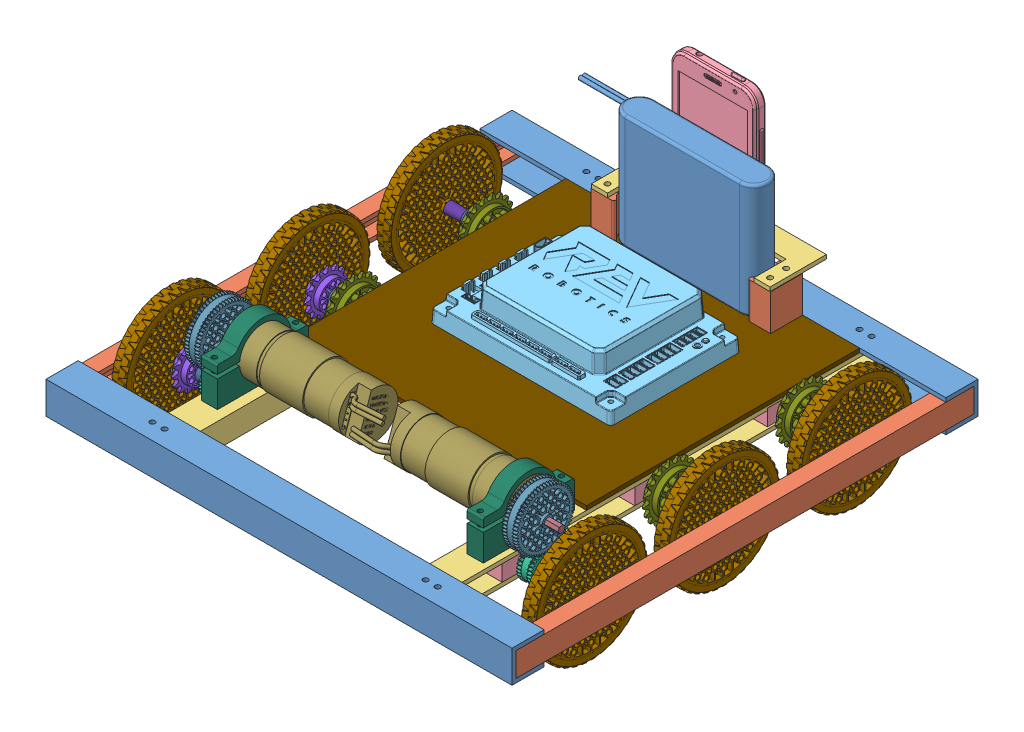
SolidWorks assembly CH_ASSEM_FULL, configuration Default. Lengths in mm.
Overall size (403.9 208.58 368.3).
104 component instances, 23 part files, 30 mates.
Components (placement in the parent):
- CH_ASSEM_Base-1: CH_ASSEM_Base [Default] at (-90.7761 -10.2499 -116.5851) size (368.3 25.4 368.3)
  - CH_FrontBackChannel-2: CH_FrontBackChannel [Default] at (378.7562 204.4057 248.334) x (0 1 0) z (0 0 1) size (25.4 368.3 25.4)
  - CH_SideOuterChannel-2: CH_SideOuterChannel [Default] at (23.1562 207.5807 226.109) x (0 1 0) z (1 0 0) size (19.05 361.95 12.7)
  - CH_FrontBackChannel-3: CH_FrontBackChannel [Default] at (378.7562 229.8057 565.834) x (0 -1 0) z (0 0 -1) size (25.4 368.3 25.4)
  - CH_SideInnerChannel-3: CH_SideInnerChannel [Default] at (78.5282 207.5807 588.059) x (0 1 0) z (-1 0 0) size (19.05 361.95 25.4)
  - CH_SideInnerChannel-4: CH_SideInnerChannel [Default] at (310.6842 226.6307 588.059) x (0 -1 0) z (1 0 0) size (19.05 361.95 25.4)
  - CH_SideOuterChannel-5: CH_SideOuterChannel [Default] at (366.0562 226.6307 226.109) x (0 -1 0) z (-1 0 0) size (19.05 361.95 12.7)
- CH_ASSEM_DriveWheel-1: CH_ASSEM_DriveWheel [Default] at (59.8291 214.6926 407.6728) x (0 0 1) z (-1 0 0) size (123.02 123.02 108.07)
  - CH_ASSEM_BearingBlockThick-1: CH_ASSEM_BearingBlockThick [Default] at (6.6511 -14.1868 37.6825) size (38.1 13.64 24.23)
    - PART_BearingBlockThick-1: PART_BearingBlockThick [Default] at (-38.1 0 12.1915) x (1 0 0) z (0 -1 0) size (38.1 22.23 12.7)
    - PART_BearingThroughBoreLong-1: PART_BearingThroughBoreLong [Default] at (-19.05 7.1437 34.4165) size (13 13 11)
  - CH_ASSEM_DriveWheelShaft-1: CH_ASSEM_DriveWheelShaft [Default] at (-19.3547 -19.6717 70.3125) x (0.866025 -0.5 0) z (0 0 1) size (90.05 90.05 94.69)
    - PART_Gear30Tooth-1: PART_Gear30Tooth [Default] at (-0.2904 14.4147 11.2865) size (24.32 24.24 15)
    - PART_HexShaft_2.875in-1: PART_HexShaft_2.875in [Default] at (-0.2904 14.4147 -9.026) size (5 5.77 73.02)
    - PART_Sprocket15Tooth-1: PART_Sprocket15Tooth [Default] at (-0.2904 14.4147 32.6365) size (33.59 33.42 15)
    - PART_TractionWheel90mm-1: PART_TractionWheel90mm [Default] at (-0.2904 14.4147 47.6365) size (90.05 90.05 80)
    - PART_ShaftCollar_0.25-1: PART_ShaftCollar_0.25 [Default] at (-0.2904 14.4147 22.7865) x (-1 0 0) z (0 0 -1) size (13 13 6.35)
  - CH_ASSEM_BearingBlockThin-2: CH_ASSEM_BearingBlockThin [Default] at (-31.4489 -14.1868 149.1656) x (-1 0 0) z (0 0 -1) size (38.1 13.64 11.53)
    - PART_BearingBlockThin-2: PART_BearingBlockThin [Default] at (-38.1 0 12.1915) x (1 0 0) z (0 -1 0) size (38.1 9.53 12.7)
    - PART_BearingThroughBoreLong-1: PART_BearingThroughBoreLong [Default] at (-19.05 7.1437 21.7165) size (13 13 11)
- PART_ASSEM_MotorHDHexRotating-1: PART_ASSEM_MotorHDHexRotating [Default] at (132.7016 260.5528 290.6085) x (0 -0.944598 0.328231) z (-1 0 0) size (38 39.44 154.16)
  - PART_MotorHDHex_Shell-1: PART_MotorHDHex_Shell [Default] at (52.6409 85.4657 114.2715) size (38 39.44 128.25)
  - PART_MotorHDHex_RotatingHex-1: PART_MotorHDHex_RotatingHex [Default] at (52.6787 94.995 172.8795) x (0.858442 -0.512911 0) z (0.512911 0.858442 0) size (5.06 33.53 5.84)
- PART_Gear60Tooth-1: PART_Gear60Tooth [Default] at (-21.7699 241.139 395.2739) x (0 0.979235 0.202728) z (1 0 0) size (47.04 47.04 15)
- PART_MotorMount-1: PART_MotorMount [Default] at (4.7296 238.7668 399.7581) x (0 0 -1) z (1 0 0) size (72 44.98 12.7)
- CH_Assem_CentreWheel-1: CH_Assem_CentreWheel [Default] at (0.9772 228.4542 315.7728) x (0 0 -1) z (-1 0 0) size (123.02 123.02 108.07)
  - CH_ASSEM_BearingBlockThick-1: CH_ASSEM_BearingBlockThick [Default] at (44.3239 15.2484 -21.1694) size (38.1 13.64 24.23)
    - PART_BearingBlockThick-1: PART_BearingBlockThick [Default] at (-38.1 0 12.1915) x (1 0 0) z (0 -1 0) size (38.1 22.23 12.7)
    - PART_BearingThroughBoreLong-1: PART_BearingThroughBoreLong [Default] at (-19.05 7.1437 34.4165) size (13 13 11)
  - CH_Assem_CentreWheelShaft-1: CH_Assem_CentreWheelShaft [Default] at (67.892 -5.5775 97.812) x (-0.866025 -0.5 0) z (0 0 -1) size (90.05 90.05 94.69)
    - PART_HexShaft_2.875in-1: PART_HexShaft_2.875in [Default] at (22.9236 45.5315 18.4024) size (5 5.77 73.02)
    - PART_Sprocket15Tooth-1: PART_Sprocket15Tooth [Default] at (22.9236 45.5315 53.7149) size (33.59 33.42 15)
    - PART_Sprocket20Tooth-1: PART_Sprocket20Tooth [Default] at (22.9236 45.5315 75.0649) size (43.5 43.5 15)
    - PART_TractionWheel90mm-1: PART_TractionWheel90mm [Default] at (22.9236 45.5315 38.7149) size (90.05 90.05 80)
    - PART_ShaftCollar_0.25-1: PART_ShaftCollar_0.25 [Default] at (22.9236 45.5315 63.5649) size (13 13 6.35)
  - CH_ASSEM_BearingBlockThin-2: CH_ASSEM_BearingBlockThin [Default] at (6.2239 15.2484 90.3137) x (-1 0 0) z (0 0 -1) size (38.1 13.64 11.53)
    - PART_BearingBlockThin-2: PART_BearingBlockThin [Default] at (-38.1 0 12.1915) x (1 0 0) z (0 -1 0) size (38.1 9.53 12.7)
    - PART_BearingThroughBoreLong-1: PART_BearingThroughBoreLong [Default] at (-19.05 7.1437 21.7165) size (13 13 11)
- CH_ASSEM_EndWheel-1: CH_ASSEM_EndWheel [Default] at (-69.4195 200.5058 204.7739) x (0 0 1) z (-1 0 0) size (123.02 123.02 108.08)
  - CH_ASSEM_BearingBlockThick-1: CH_ASSEM_BearingBlockThick [Default] at (0 0 -91.5661) size (38.1 13.64 24.23)
    - PART_BearingBlockThick-1: PART_BearingBlockThick [Default] at (-38.1 0 12.1915) x (1 0 0) z (0 -1 0) size (38.1 22.23 12.7)
    - PART_BearingThroughBoreLong-1: PART_BearingThroughBoreLong [Default] at (-19.05 7.1437 34.4165) size (13 13 11)
  - CH_ASSEM_EndWheelShaft-1: CH_ASSEM_EndWheelShaft [Default] at (-20.2483 -39.7214 30.647) x (-0.866025 0.5 0) z (0 0 -1) size (90.05 90.05 94.69)
    - PART_HexShaft_2.875in-1: PART_HexShaft_2.875in [Default] at (22.3948 41.1855 21.634) size (5 5.77 73.02)
    - PART_Spacer15mm-1: PART_Spacer15mm [Default] at (22.3948 41.1855 56.9465) size (8.79 8.79 15)
    - PART_Sprocket20Tooth-1: PART_Sprocket20Tooth [Default] at (22.3948 41.1855 78.2965) size (43.5 43.5 15)
    - PART_TractionWheel90mm-1: PART_TractionWheel90mm [Default] at (22.3948 41.1855 41.9465) size (90.05 90.05 80)
    - PART_ShaftCollar_0.25-1: PART_ShaftCollar_0.25 [Default] at (22.3948 41.1855 66.7965) x (-1 0 0) z (0 0 1) size (13 13 6.35)
  - CH_ASSEM_BearingBlockThin-2: CH_ASSEM_BearingBlockThin [Default] at (-38.1 0 19.917) x (-1 0 0) z (0 0 -1) size (38.1 13.64 11.53)
    - PART_BearingBlockThin-2: PART_BearingBlockThin [Default] at (-38.1 0 12.1915) x (1 0 0) z (0 -1 0) size (38.1 9.53 12.7)
    - PART_BearingThroughBoreLong-1: PART_BearingThroughBoreLong [Default] at (-19.05 7.1437 21.7165) size (13 13 11)
- PART_ASSEM_MotorHDHexRotating-2: PART_ASSEM_MotorHDHexRotating [Default] at (74.9586 161.104 325.1651) x (0 0.944598 -0.328231) z (1 0 0) size (38 39.44 154.16)
  - PART_MotorHDHex_Shell-1: PART_MotorHDHex_Shell [Default] at (52.6409 85.4657 114.2715) size (38 39.44 128.25)
  - PART_MotorHDHex_RotatingHex-1: PART_MotorHDHex_RotatingHex [Default] at (52.6787 94.995 172.8795) x (0.858442 -0.512911 0) z (0.512911 0.858442 0) size (5.06 33.53 5.84)
- CH_ASSEM_DriveWheel-2: CH_ASSEM_DriveWheel [Default] at (147.8311 214.6926 382.8751) x (0 0 -1) z (1 0 0) size (123.02 123.02 108.07)
  - CH_ASSEM_BearingBlockThick-1: CH_ASSEM_BearingBlockThick [Default] at (6.6511 -14.1868 37.6825) size (38.1 13.64 24.23)
    - PART_BearingBlockThick-1: PART_BearingBlockThick [Default] at (-38.1 0 12.1915) x (1 0 0) z (0 -1 0) size (38.1 22.23 12.7)
    - PART_BearingThroughBoreLong-1: PART_BearingThroughBoreLong [Default] at (-19.05 7.1437 34.4165) size (13 13 11)
  - CH_ASSEM_DriveWheelShaft-1: CH_ASSEM_DriveWheelShaft [Default] at (-19.3547 -19.6717 70.3125) x (0.866025 -0.5 0) z (0 0 1) size (90.05 90.05 94.69)
    - PART_Gear30Tooth-1: PART_Gear30Tooth [Default] at (-0.2904 14.4147 11.2865) size (24.32 24.24 15)
    - PART_HexShaft_2.875in-1: PART_HexShaft_2.875in [Default] at (-0.2904 14.4147 -9.026) size (5 5.77 73.02)
    - PART_Sprocket15Tooth-1: PART_Sprocket15Tooth [Default] at (-0.2904 14.4147 32.6365) size (33.59 33.42 15)
    - PART_TractionWheel90mm-1: PART_TractionWheel90mm [Default] at (-0.2904 14.4147 47.6365) size (90.05 90.05 80)
    - PART_ShaftCollar_0.25-1: PART_ShaftCollar_0.25 [Default] at (-0.2904 14.4147 22.7865) x (-1 0 0) z (0 0 -1) size (13 13 6.35)
  - CH_ASSEM_BearingBlockThin-2: CH_ASSEM_BearingBlockThin [Default] at (-31.4489 -14.1868 149.1656) x (-1 0 0) z (0 0 -1) size (38.1 13.64 11.53)
    - PART_BearingBlockThin-2: PART_BearingBlockThin [Default] at (-38.1 0 12.1915) x (1 0 0) z (0 -1 0) size (38.1 9.53 12.7)
    - PART_BearingThroughBoreLong-1: PART_BearingThroughBoreLong [Default] at (-19.05 7.1437 21.7165) size (13 13 11)
- PART_Gear60Tooth-2: PART_Gear60Tooth [Default] at (229.4301 241.139 395.2739) x (0 -0.979235 -0.202728) z (-1 0 0) size (47.04 47.04 15)
- PART_MotorMount-2: PART_MotorMount [Default] at (214.8296 238.7668 399.7581) x (0 0 -1) z (1 0 0) size (72 44.98 12.7)
- CH_Assem_CentreWheel-2: CH_Assem_CentreWheel [Default] at (206.683 228.4542 265.2251) x (0 0 1) z (1 0 0) size (123.02 123.02 108.07)
  - CH_ASSEM_BearingBlockThick-1: CH_ASSEM_BearingBlockThick [Default] at (44.3239 15.2484 -21.1694) size (38.1 13.64 24.23)
    - PART_BearingBlockThick-1: PART_BearingBlockThick [Default] at (-38.1 0 12.1915) x (1 0 0) z (0 -1 0) size (38.1 22.23 12.7)
    - PART_BearingThroughBoreLong-1: PART_BearingThroughBoreLong [Default] at (-19.05 7.1437 34.4165) size (13 13 11)
  - CH_Assem_CentreWheelShaft-1: CH_Assem_CentreWheelShaft [Default] at (67.892 -5.5775 97.812) x (-0.866025 -0.5 0) z (0 0 -1) size (90.05 90.05 94.69)
    - PART_HexShaft_2.875in-1: PART_HexShaft_2.875in [Default] at (22.9236 45.5315 18.4024) size (5 5.77 73.02)
    - PART_Sprocket15Tooth-1: PART_Sprocket15Tooth [Default] at (22.9236 45.5315 53.7149) size (33.59 33.42 15)
    - PART_Sprocket20Tooth-1: PART_Sprocket20Tooth [Default] at (22.9236 45.5315 75.0649) size (43.5 43.5 15)
    - PART_TractionWheel90mm-1: PART_TractionWheel90mm [Default] at (22.9236 45.5315 38.7149) size (90.05 90.05 80)
    - PART_ShaftCollar_0.25-1: PART_ShaftCollar_0.25 [Default] at (22.9236 45.5315 63.5649) size (13 13 6.35)
  - CH_ASSEM_BearingBlockThin-2: CH_ASSEM_BearingBlockThin [Default] at (6.2239 15.2484 90.3137) x (-1 0 0) z (0 0 -1) size (38.1 13.64 11.53)
    - PART_BearingBlockThin-2: PART_BearingBlockThin [Default] at (-38.1 0 12.1915) x (1 0 0) z (0 -1 0) size (38.1 9.53 12.7)
    - PART_BearingThroughBoreLong-1: PART_BearingThroughBoreLong [Default] at (-19.05 7.1437 21.7165) size (13 13 11)
- CH_ASSEM_EndWheel-2: CH_ASSEM_EndWheel [Default] at (277.0797 214.7933 204.7739) x (0 0 1) z (1 0 0) size (123.02 123.02 108.08)
  - CH_ASSEM_BearingBlockThick-1: CH_ASSEM_BearingBlockThick [Default] at (0 0 -91.5661) size (38.1 13.64 24.23)
    - PART_BearingBlockThick-1: PART_BearingBlockThick [Default] at (-38.1 0 12.1915) x (1 0 0) z (0 -1 0) size (38.1 22.23 12.7)
    - PART_BearingThroughBoreLong-1: PART_BearingThroughBoreLong [Default] at (-19.05 7.1437 34.4165) size (13 13 11)
  - CH_ASSEM_EndWheelShaft-1: CH_ASSEM_EndWheelShaft [Default] at (-20.2483 -39.7214 30.647) x (-0.866025 0.5 0) z (0 0 -1) size (90.05 90.05 94.69)
    - PART_HexShaft_2.875in-1: PART_HexShaft_2.875in [Default] at (22.3948 41.1855 21.634) size (5 5.77 73.02)
    - PART_Spacer15mm-1: PART_Spacer15mm [Default] at (22.3948 41.1855 56.9465) size (8.79 8.79 15)
    - PART_Sprocket20Tooth-1: PART_Sprocket20Tooth [Default] at (22.3948 41.1855 78.2965) size (43.5 43.5 15)
    - PART_TractionWheel90mm-1: PART_TractionWheel90mm [Default] at (22.3948 41.1855 41.9465) size (90.05 90.05 80)
    - PART_ShaftCollar_0.25-1: PART_ShaftCollar_0.25 [Default] at (22.3948 41.1855 66.7965) x (-1 0 0) z (0 0 1) size (13 13 6.35)
  - CH_ASSEM_BearingBlockThin-2: CH_ASSEM_BearingBlockThin [Default] at (-38.1 0 19.917) x (-1 0 0) z (0 0 -1) size (38.1 13.64 11.53)
    - PART_BearingBlockThin-2: PART_BearingBlockThin [Default] at (-38.1 0 12.1915) x (1 0 0) z (0 -1 0) size (38.1 9.53 12.7)
    - PART_BearingThroughBoreLong-1: PART_BearingThroughBoreLong [Default] at (-19.05 7.1437 21.7165) size (13 13 11)
- CH_BaseSheet-1: CH_BaseSheet [Default] at (-12.2479 216.3808 347.6489) size (232.16 3.17 215.9)
- CH_ASSEM_BatteryPhone-1: CH_ASSEM_BatteryPhone [Default] at (39.7502 187.7674 170.7548) x (0 0 -1) z (1 0 0) size (44.45 133.58 161.51)
  - PART_BatterySlim12V-1: PART_BatterySlim12V [Default] at (26.3058 77.0384 64.08) x (0 -1 0) z (0 0 1) size (90.56 23.03 147.25)
  - PART_SlimBatteryClip-1: PART_SlimBatteryClip [Default] at (39.0058 31.7884 107.3076) x (0 0 -1) z (1 0 0) size (18.01 28.57 25.4)
  - PART_SlimBatteryClip-2: PART_SlimBatteryClip [Default] at (13.6058 31.7884 20.8523) x (0 0 1) z (-1 0 0) size (18.01 28.57 25.4)
  - PART_PhoneSupportSheet-1: PART_PhoneSupportSheet [Default] at (58.0558 60.3634 134.692) x (0 0 -1) z (1 0 0) size (141.22 3.17 44.45)
  - PART_ZTESpeed-1: PART_ZTESpeed [Default] at (40.0121 98.6181 70.154) x (0 0 1) z (-1 0 0) size (68.17 133.58 10.49)
- PART_ExpansionHub-1: PART_ExpansionHub [Default] at (103.8301 219.4847 232.4629) x (0 0 1) z (-1 0 0) size (103 29.58 143)
- PART_ShaftCollar_0.25-1: PART_ShaftCollar_0.25 [Default] at (-31.6199 241.0895 395.2112) x (0 0.979235 0.202728) z (-1 0 0) size (13 13 6.35)
Mates (geometry in assembly coordinates):
- Coincident7: coincident anti-aligned: plane of PART_ASSEM_MotorHDHexRotating-1/PART_MotorHDHex_RotatingHex-1 through (-6.6499 243.3595 397.1726) normal (0 0.31405 0.949406); plane of PART_Gear60Tooth-1 through (-21.7699 240.5538 398.1007) normal (0 -0.31405 -0.949406)
- Coincident8: coincident anti-aligned: plane of PART_ASSEM_MotorHDHexRotating-1/PART_MotorHDHex_RotatingHex-1 through (-6.6499 238.4052 396.147) normal (0 -0.979235 -0.202728); plane of PART_Gear60Tooth-1 through (-21.7699 238.9835 393.3537) normal (0 0.979235 0.202728)
- Coincident9: coincident anti-aligned: plane of PART_ASSEM_MotorHDHexRotating-1/PART_MotorHDHex_Shell-1 through (-14.2699 241.1784 395.2296) normal (-1 0 0); plane of PART_Gear60Tooth-1 through (-14.2699 241.139 395.2739) normal (1 0 0)
- Concentric2: concentric anti-aligned: cylinder of PART_ASSEM_MotorHDHexRotating-1/PART_MotorHDHex_Shell-1 through (-7.5699 238.8808 388.6175) axis (1 0 0) radius 18.5; cylinder of PART_MotorMount-1 through (5.1301 238.8808 388.6175) axis (-1 0 0) radius 18.5
- Coincident11: coincident aligned: plane of PART_ASSEM_MotorHDHexRotating-1/PART_MotorHDHex_Shell-1 through (-7.5699 238.8808 388.6175) normal (-1 0 0); plane of PART_MotorMount-1 through (-7.5699 238.8808 388.6175) normal (-1 0 0)
- Coincident12: coincident anti-aligned: plane of CH_ASSEM_Base-1/CH_SideInnerChannel-3 through (13.1521 216.3808 109.5239) normal (0 1 0); plane of PART_MotorMount-1 through (5.1301 216.3808 352.6175) normal (0 -1 0)
- Coincident13: coincident aligned: plane of CH_ASSEM_DriveWheel-1/CH_ASSEM_DriveWheelShaft-1/PART_Gear30Tooth-1 through (-27.2699 207.6496 395.2739) normal (-1 0 0); plane of PART_Gear60Tooth-1 through (-27.2699 241.139 395.2739) normal (-1 0 0)
- Tangent2: tangent anti-aligned: cylinder of CH_ASSEM_DriveWheel-1/CH_ASSEM_DriveWheelShaft-1/PART_Gear30Tooth-1 through (-19.2299 207.6496 395.2739) axis (-1 0 0) radius 11.1197; cylinder of PART_Gear60Tooth-1 through (-24.3099 241.139 395.2739) axis (1 0 0) radius 22.3697
- Coincident16: coincident anti-aligned: plane of CH_ASSEM_Base-1/CH_SideInnerChannel-3 through (9.9771 200.5058 109.5239) normal (0 1 0); plane of CH_ASSEM_DriveWheel-1/CH_ASSEM_BearingBlockThick-1/PART_BearingBlockThick-1 through (-12.2699 200.5058 376.2239) normal (0 -1 0)
- Distance2: distance = 57.15 mm anti-aligned: plane of CH_ASSEM_Base-1/CH_FrontBackChannel-3 through (-80.3199 197.3308 471.4739) normal (0 0 -1); plane of CH_ASSEM_DriveWheel-1/CH_ASSEM_BearingBlockThick-1/PART_BearingBlockThick-1 through (-12.2699 200.5058 414.3239) normal (0 0 1)
- Coincident20: coincident anti-aligned: plane of CH_ASSEM_Base-1/CH_SideInnerChannel-3 through (9.9771 200.5058 109.5239) normal (0 1 0); plane of CH_ASSEM_EndWheel-1/CH_ASSEM_BearingBlockThick-1/PART_BearingBlockThick-1 through (-12.2699 200.5058 166.6739) normal (0 -1 0)
- Width1: width aligned: plane of CH_ASSEM_Base-1/CH_FrontBackChannel-2 through (-80.3199 216.3808 109.5239) normal (0 0 1); plane of CH_ASSEM_Base-1/CH_FrontBackChannel-3 through (-80.3199 197.3308 471.4739) normal (0 0 -1); plane of CH_ASSEM_EndWheel-1/CH_ASSEM_BearingBlockThick-1/PART_BearingBlockThick-1 through (-12.2699 200.5058 204.7739) normal (0 0 1); plane of CH_ASSEM_DriveWheel-1/CH_ASSEM_BearingBlockThick-1/PART_BearingBlockThick-1 through (-12.2699 200.5058 376.2239) normal (0 0 -1)
- Coincident23: coincident anti-aligned: plane of CH_ASSEM_Base-1/CH_SideOuterChannel-2 through (-77.1449 200.5058 471.4739) normal (0 1 0); plane of CH_Assem_CentreWheel-1/CH_ASSEM_BearingBlockThin-2/PART_BearingBlockThin-2 through (-67.6199 200.5058 271.4489) normal (0 -1 0)
- Width3: width aligned: plane of CH_ASSEM_Base-1/CH_FrontBackChannel-2 through (-80.3199 216.3808 109.5239) normal (0 0 1); plane of CH_ASSEM_Base-1/CH_FrontBackChannel-3 through (-80.3199 197.3308 471.4739) normal (0 0 -1); plane of CH_Assem_CentreWheel-1/CH_ASSEM_BearingBlockThick-1/PART_BearingBlockThick-1 through (-12.2699 213.2058 309.5489) normal (0 0 1); plane of CH_Assem_CentreWheel-1/CH_ASSEM_BearingBlockThick-1/PART_BearingBlockThick-1 through (-12.2699 213.2058 271.4489) normal (0 0 -1)
- Width4: width: plane of CH_ASSEM_DriveWheel-1/CH_ASSEM_BearingBlockThick-1/PART_BearingBlockThick-1 through (-12.2699 200.5058 414.3239) normal (0 0 1); plane of CH_ASSEM_DriveWheel-1/CH_ASSEM_BearingBlockThick-1/PART_BearingBlockThick-1 through (-12.2699 200.5058 376.2239) normal (0 0 -1); cylinder of PART_Gear60Tooth-1 through (-24.3099 241.139 395.2739) axis (1 0 0) radius 22.3697
- Coincident24: coincident anti-aligned: plane of CH_ASSEM_Base-1/CH_SideInnerChannel-4 through (219.9081 216.3808 109.5239) normal (0 1 0); plane of CH_BaseSheet-1 through (-12.2479 216.3808 347.6489) normal (0 -1 0)
- Coincident25: coincident anti-aligned: plane of CH_ASSEM_Base-1/CH_FrontBackChannel-2 through (-80.3199 219.5558 131.7489) normal (0 0 1); plane of CH_BaseSheet-1 through (-12.2479 219.5558 131.7489) normal (0 0 -1)
- Coincident27: coincident anti-aligned: plane of CH_BaseSheet-1 through (-12.2479 219.5558 347.6489) normal (0 1 0); plane of CH_ASSEM_BatteryPhone-1/PART_BatterySlim12V-1 through (103.8301 219.5558 144.4489) normal (0 -1 0)
- Coincident28: coincident aligned: plane of CH_ASSEM_Base-1 through (103.8301 -10.2499 -116.5851) normal (1 0 0); plane of CH_ASSEM_BatteryPhone-1/PART_BatterySlim12V-1 through (103.8301 264.8058 144.4489) normal (1 0 0)
- Coincident29: coincident anti-aligned: plane of CH_ASSEM_Base-1 through (103.8301 -10.2499 -116.5851) normal (1 0 0); plane of PART_ExpansionHub-1 through (103.8301 219.4847 232.4629) normal (-1 0 0)
- Coincident30: coincident anti-aligned: plane of CH_BaseSheet-1 through (-12.2479 219.5558 347.6489) normal (0 1 0); plane of PART_ExpansionHub-1 through (103.8301 219.5558 232.4629) normal (0 -1 0)
- Distance5: distance = 25.4 mm: line of PART_ExpansionHub-1 through (59.0498 247.1959 182.5489) axis (1 0 0); plane of CH_ASSEM_BatteryPhone-1/PART_SlimBatteryClip-1 through (147.0577 248.1308 157.1489) normal (0 0 1)
- Coincident31: coincident anti-aligned: line of CH_BaseSheet-1 through (219.9081 219.5558 131.7489) axis (-1 0 0); line of CH_ASSEM_BatteryPhone-1/PART_SlimBatteryClip-2 through (32.8212 219.5558 131.7489) axis (1 0 0)
- Coincident37: coincident aligned: plane of CH_ASSEM_Base-1/CH_SideInnerChannel-3 through (-12.2479 216.3808 109.5239) normal (-1 0 0); plane of CH_BaseSheet-1 through (-12.2479 219.5558 347.6489) normal (-1 0 0)
- Coincident38: coincident anti-aligned: plane of CH_ASSEM_Base-1/CH_SideOuterChannel-2 through (-77.1449 213.2058 471.4739) normal (1 0 0); plane of CH_Assem_CentreWheel-1/CH_ASSEM_BearingBlockThin-2/PART_BearingBlockThin-2 through (-77.1449 213.2058 271.4489) normal (-1 0 0)
- Coincident39: coincident anti-aligned: plane of CH_ASSEM_Base-1/CH_SideOuterChannel-2 through (-77.1449 213.2058 471.4739) normal (1 0 0); plane of CH_ASSEM_EndWheel-1/CH_ASSEM_BearingBlockThin-2/PART_BearingBlockThin-2 through (-77.1449 200.5058 204.7739) normal (-1 0 0)
- Coincident40: coincident anti-aligned: plane of CH_ASSEM_Base-1/CH_SideOuterChannel-2 through (-77.1449 213.2058 471.4739) normal (1 0 0); plane of CH_ASSEM_DriveWheel-1/CH_ASSEM_BearingBlockThin-2/PART_BearingBlockThin-2 through (-77.1449 200.5058 414.3239) normal (-1 0 0)
- Coincident41: coincident anti-aligned: plane of PART_Gear60Tooth-1 through (-29.2699 241.139 395.2739) normal (-1 0 0); plane of PART_ShaftCollar_0.25-1 through (-29.2699 247.4545 396.529) normal (1 0 0)
- Coincident43: coincident: line of PART_ASSEM_MotorHDHexRotating-1/PART_MotorHDHex_RotatingHex-1 through (-6.6499 243.3595 397.1726) axis (-1 0 0); cylinder of PART_ShaftCollar_0.25-1 through (-35.6199 241.0895 395.2112) axis (-1 0 0) radius 3
- Coincident45: coincident: line of PART_ASSEM_MotorHDHexRotating-1/PART_MotorHDHex_RotatingHex-1 through (-6.6499 243.9517 394.3123) axis (-1 0 0); cylinder of PART_ShaftCollar_0.25-1 through (-35.6199 241.0895 395.2112) axis (-1 0 0) radius 3
